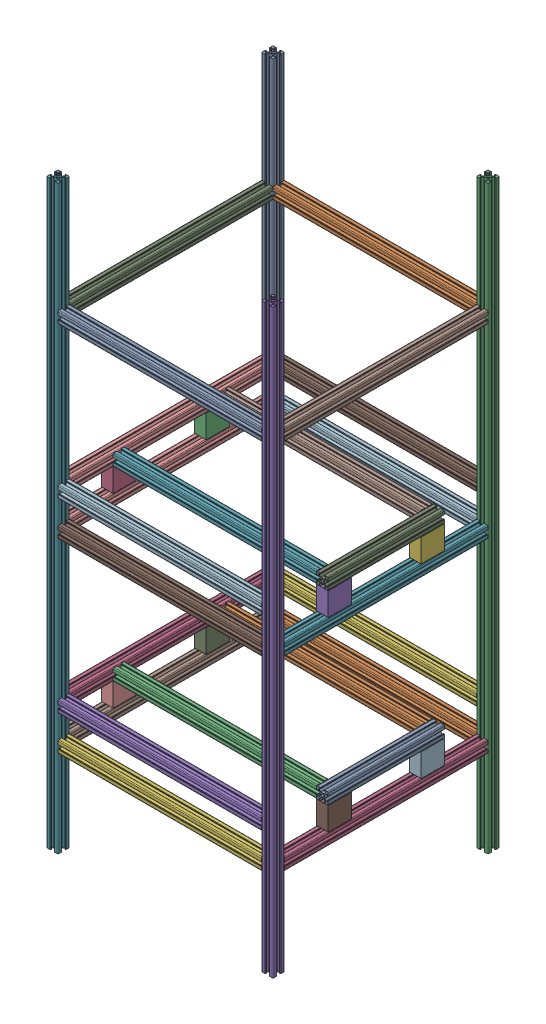
SolidWorks assembly 货架, configuration 默认. Lengths in mm.
Overall size (390 1000 390).
36 component instances, 4 part files, 105 mates.
Components (placement in the parent):
- 竖直1000型材1-1: 竖直1000型材1 [默认<按加工>] at (-170.1901 -508.4769 0) size (20 1000 20)
- 水平350型材1-1: 水平350型材1 [默认<按加工>] at (-160.1901 -348.4769 0) size (350 20 20)
- 竖直1000型材1-2: 竖直1000型材1 [默认<按加工>] at (199.8099 -508.4769 0) size (20 1000 20)
- 水平350型材1-2: 水平350型材1 [默认<按加工>] at (199.8099 -348.4769 10) x (0 0 1) z (-1 0 0) size (350 20 20)
- 竖直1000型材1-3: 竖直1000型材1 [默认<按加工>] at (199.8099 -508.4769 370) size (20 1000 20)
- 水平350型材1-3: 水平350型材1 [默认<按加工>] at (-160.1901 -348.4769 370) size (350 20 20)
- 竖直1000型材1-4: 竖直1000型材1 [默认<按加工>] at (-170.1901 -508.4769 370) size (20 1000 20)
- 水平350型材1-4: 水平350型材1 [默认<按加工>] at (-170.1901 -348.4769 10) x (0 0 1) z (-1 0 0) size (350 20 20)
- 垫高块40x40-1: 垫高块40x40 [默认] at (-180.1901 -338.4769 125) size (20 40 40)
- 垫高块40x40-2: 垫高块40x40 [默认] at (-180.1901 -338.4769 285) size (20 40 40)
- 垫高块40x40-3: 垫高块40x40 [默认] at (189.8099 -338.4769 285) size (20 40 40)
- 垫高块40x40-4: 垫高块40x40 [默认] at (189.8099 -338.4769 125) size (20 40 40)
- 水平200型材1-1: 水平200型材1 [默认<按加工>] at (199.8099 -288.4769 85) x (0 0 1) z (-1 0 0) size (200 20 20)
- 水平350型材1-5: 水平350型材1 [默认<按加工>] at (-160.1901 -288.4769 95) size (350 20 20)
- 水平350型材1-6: 水平350型材1 [默认<按加工>] at (-160.1901 -288.4769 275) size (350 20 20)
- 水平350型材1-7: 水平350型材1 [默认<按加工>] at (-170.1901 -288.4769 360) x (0 0 -1) z (1 0 0) size (350 20 20)
- 水平350型材1-8: 水平350型材1 [默认<按加工>] at (-160.1901 -288.4769 370) size (350 20 20)
- 水平350型材1-9: 水平350型材1 [默认<按加工>] at (-160.1901 -288.4769 0) size (350 20 20)
- 水平350型材1-10: 水平350型材1 [默认<按加工>] at (199.8099 -28.4769 10) x (0 0 1) z (-1 0 0) size (350 20 20)
- 水平350型材1-11: 水平350型材1 [默认<按加工>] at (199.8099 291.5231 10) x (0 0 1) z (-1 0 0) size (350 20 20)
- 水平350型材1-12: 水平350型材1 [默认<按加工>] at (-170.1901 291.5231 10) x (0 0 1) z (-1 0 0) size (350 20 20)
- 水平350型材1-13: 水平350型材1 [默认<按加工>] at (-170.1901 -28.4769 360) x (0 0 -1) z (1 0 0) size (350 20 20)
- 水平350型材1-14: 水平350型材1 [默认<按加工>] at (-160.1901 -28.4769 370) size (350 20 20)
- 水平350型材1-15: 水平350型材1 [默认<按加工>] at (-160.1901 -28.4769 0) size (350 20 20)
- 水平350型材1-16: 水平350型材1 [默认<按加工>] at (-160.1901 291.5231 370) size (350 20 20)
- 水平350型材1-17: 水平350型材1 [默认<按加工>] at (-160.1901 291.5231 0) size (350 20 20)
- 垫高块40x40-5: 垫高块40x40 [默认] at (-180.1901 -18.4769 125) size (20 40 40)
- 垫高块40x40-6: 垫高块40x40 [默认] at (-180.1901 -18.4769 285) size (20 40 40)
- 垫高块40x40-7: 垫高块40x40 [默认] at (189.8099 -18.4769 285) size (20 40 40)
- 垫高块40x40-8: 垫高块40x40 [默认] at (189.8099 -18.4769 125) size (20 40 40)
- 水平350型材1-18: 水平350型材1 [默认<按加工>] at (-160.1901 31.5231 275) size (350 20 20)
- 水平350型材1-19: 水平350型材1 [默认<按加工>] at (-160.1901 31.5231 95) size (350 20 20)
- 水平200型材1-3: 水平200型材1 [默认<按加工>] at (199.8099 31.5231 85) x (0 0 1) z (-1 0 0) size (200 20 20)
- 水平350型材1-20: 水平350型材1 [默认<按加工>] at (-170.1901 31.5231 10) x (0 0 1) z (-1 0 0) size (350 20 20)
- 水平350型材1-21: 水平350型材1 [默认<按加工>] at (-160.1901 31.5231 0) size (350 20 20)
- 水平350型材1-22: 水平350型材1 [默认<按加工>] at (-160.1901 31.5231 370) size (350 20 20)
Mates (geometry in assembly coordinates):
- 重合1: coincident anti-aligned: plane of 竖直1000型材1-1 through (-160.1901 491.5231 -8.5) normal (1 0 0); plane of 水平350型材1-1 through (-160.1901 -339.9769 8.5) normal (-1 0 0)
- 重合2: coincident aligned: plane of 竖直1000型材1-1 through (-166.5901 491.5231 10) normal (0 0 1); plane of 水平350型材1-1 through (189.8099 -344.8769 10) normal (0 0 1)
- 距离1: distance = 150 mm aligned: plane of 水平350型材1-1 through (189.8099 -358.4769 8.5) normal (0 -1 0); plane of 竖直1000型材1-1 through (-161.6901 -508.4769 8.5) normal (0 -1 0)
- 重合4: coincident anti-aligned: plane of 水平350型材1-1 through (189.8099 -339.9769 8.5) normal (1 0 0); plane of 竖直1000型材1-2 through (189.8099 491.5231 8.5) normal (-1 0 0)
- 重合5: coincident aligned: plane of 水平350型材1-1 through (189.8099 -344.8769 10) normal (0 0 1); plane of 竖直1000型材1-2 through (191.3099 491.5231 10) normal (0 0 1)
- 距离2: distance = 150 mm aligned: plane of 竖直1000型材1-2 through (208.3099 -508.4769 8.5) normal (0 -1 0); plane of 水平350型材1-1 through (189.8099 -358.4769 8.5) normal (0 -1 0)
- 重合7: coincident anti-aligned: plane of 竖直1000型材1-2 through (203.4099 491.5231 10) normal (0 0 1); plane of 水平350型材1-2 through (191.3099 -339.9769 10) normal (0 0 -1)
- 重合8: coincident aligned: plane of 竖直1000型材1-2 through (189.8099 491.5231 8.5) normal (-1 0 0); plane of 水平350型材1-2 through (189.8099 -344.8769 360) normal (-1 0 0)
- 重合9: coincident aligned: plane of 水平350型材1-1 through (189.8099 -338.4769 3.6) normal (0 1 0); plane of 水平350型材1-2 through (208.3099 -338.4769 360) normal (0 1 0)
- 重合10: coincident anti-aligned: plane of 水平350型材1-2 through (191.3099 -339.9769 360) normal (0 0 1); plane of 竖直1000型材1-3 through (208.3099 491.5231 360) normal (0 0 -1)
- 重合11: coincident aligned: plane of 水平350型材1-2 through (189.8099 -344.8769 360) normal (-1 0 0); plane of 竖直1000型材1-3 through (189.8099 491.5231 366.4) normal (-1 0 0)
- 距离3: distance = 150 mm aligned: plane of 竖直1000型材1-3 through (208.3099 -508.4769 378.5) normal (0 -1 0); plane of 水平350型材1-2 through (191.3099 -358.4769 360) normal (0 -1 0)
- 重合13: coincident anti-aligned: plane of 竖直1000型材1-3 through (189.8099 491.5231 378.5) normal (-1 0 0); plane of 水平350型材1-3 through (189.8099 -339.9769 378.5) normal (1 0 0)
- 重合14: coincident aligned: plane of 竖直1000型材1-3 through (191.3099 491.5231 380) normal (0 0 1); plane of 水平350型材1-3 through (189.8099 -344.8769 380) normal (0 0 1)
- 重合15: coincident aligned: plane of 水平350型材1-2 through (208.3099 -338.4769 360) normal (0 1 0); plane of 水平350型材1-3 through (189.8099 -338.4769 361.5) normal (0 1 0)
- 重合16: coincident anti-aligned: plane of 水平350型材1-3 through (-160.1901 -339.9769 378.5) normal (-1 0 0); plane of 竖直1000型材1-4 through (-160.1901 491.5231 361.5) normal (1 0 0)
- 重合17: coincident aligned: plane of 水平350型材1-3 through (189.8099 -344.8769 380) normal (0 0 1); plane of 竖直1000型材1-4 through (-166.5901 491.5231 380) normal (0 0 1)
- 距离4: distance = 150 mm aligned: plane of 竖直1000型材1-4 through (-161.6901 -508.4769 378.5) normal (0 -1 0); plane of 水平350型材1-3 through (189.8099 -358.4769 378.5) normal (0 -1 0)
- 重合19: coincident anti-aligned: plane of 竖直1000型材1-1 through (-166.5901 491.5231 10) normal (0 0 1); plane of 水平350型材1-4 through (-178.6901 -339.9769 10) normal (0 0 -1)
- 重合20: coincident aligned: plane of 竖直1000型材1-1 through (-180.1901 491.5231 8.5) normal (-1 0 0); plane of 水平350型材1-4 through (-180.1901 -344.8769 360) normal (-1 0 0)
- 重合21: coincident aligned: plane of 水平350型材1-3 through (189.8099 -338.4769 361.5) normal (0 1 0); plane of 水平350型材1-4 through (-161.6901 -338.4769 360) normal (0 1 0)
- 重合22: coincident anti-aligned: plane of 水平350型材1-4 through (-161.6901 -338.4769 360) normal (0 1 0); plane of 垫高块40x40-1 through (-160.1901 -338.4769 125) normal (0 -1 0)
- 重合23: coincident aligned: plane of 水平350型材1-4 through (-180.1901 -344.8769 360) normal (-1 0 0); plane of 垫高块40x40-1 through (-180.1901 -338.4769 125) normal (-1 0 0)
- 距离5: distance = 75 mm anti-aligned: plane of 垫高块40x40-1 through (-160.1901 -338.4769 85) normal (0 0 -1); plane of 竖直1000型材1-1 through (-166.5901 491.5231 10) normal (0 0 1)
- 重合25: coincident anti-aligned: plane of 水平350型材1-4 through (-161.6901 -338.4769 360) normal (0 1 0); plane of 垫高块40x40-2 through (-160.1901 -338.4769 285) normal (0 -1 0)
- 重合26: coincident aligned: plane of 水平350型材1-4 through (-180.1901 -344.8769 360) normal (-1 0 0); plane of 垫高块40x40-2 through (-180.1901 -338.4769 285) normal (-1 0 0)
- 距离6: distance = 75 mm anti-aligned: plane of 垫高块40x40-2 through (-160.1901 -338.4769 285) normal (0 0 1); plane of 竖直1000型材1-4 through (-161.6901 491.5231 360) normal (0 0 -1)
- 重合28: coincident anti-aligned: plane of 水平350型材1-2 through (196.2099 -338.4769 360) normal (0 1 0); plane of 垫高块40x40-3 through (209.8099 -338.4769 285) normal (0 -1 0)
- 重合29: coincident aligned: plane of 水平350型材1-2 through (209.8099 -352.0769 360) normal (1 0 0); plane of 垫高块40x40-3 through (209.8099 -338.4769 285) normal (1 0 0)
- 距离7: distance = 75 mm anti-aligned: plane of 竖直1000型材1-3 through (196.2099 491.5231 360) normal (0 0 -1); plane of 垫高块40x40-3 through (209.8099 -338.4769 285) normal (0 0 1)
- 重合30: coincident aligned: plane of 水平350型材1-2 through (209.8099 -339.9769 360) normal (1 0 0); plane of 垫高块40x40-4 through (209.8099 -338.4769 125) normal (1 0 0)
- 重合32: coincident anti-aligned: plane of 水平350型材1-2 through (196.2099 -338.4769 360) normal (0 1 0); plane of 垫高块40x40-4 through (209.8099 -338.4769 125) normal (0 -1 0)
- 距离8: distance = 75 mm anti-aligned: plane of 垫高块40x40-4 through (209.8099 -338.4769 85) normal (0 0 -1); plane of 竖直1000型材1-2 through (191.3099 491.5231 10) normal (0 0 1)
- 重合34: coincident aligned: plane of 垫高块40x40-3 through (209.8099 -338.4769 285) normal (0 0 1); plane of 水平200型材1-1 through (191.3099 -279.9769 285) normal (0 0 1)
- 重合35: coincident anti-aligned: plane of 垫高块40x40-3 through (209.8099 -298.4769 285) normal (0 1 0); plane of 水平200型材1-1 through (203.4099 -298.4769 285) normal (0 -1 0)
- 重合36: coincident aligned: plane of 垫高块40x40-3 through (209.8099 -338.4769 285) normal (1 0 0); plane of 水平200型材1-1 through (209.8099 -279.9769 285) normal (1 0 0)
- 重合40: coincident anti-aligned: plane of 水平200型材1-1 through (189.8099 -284.8769 285) normal (-1 0 0); plane of 水平350型材1-5 through (189.8099 -279.9769 103.5) normal (1 0 0)
- 重合41: coincident aligned: plane of 水平200型材1-1 through (208.3099 -278.4769 285) normal (0 1 0); plane of 水平350型材1-5 through (189.8099 -278.4769 98.6) normal (0 1 0)
- 重合42: coincident aligned: plane of 水平200型材1-1 through (191.3099 -279.9769 85) normal (0 0 -1); plane of 水平350型材1-5 through (189.8099 -279.9769 85) normal (0 0 -1)
- 重合46: coincident anti-aligned: plane of 竖直1000型材1-4 through (-161.6901 491.5231 360) normal (0 0 -1); plane of 水平350型材1-7 through (-161.6901 -279.9769 360) normal (0 0 1)
- 重合47: coincident anti-aligned: plane of 水平350型材1-5 through (-160.1901 -279.9769 103.5) normal (-1 0 0); plane of 水平350型材1-7 through (-160.1901 -284.8769 10) normal (1 0 0)
- 重合48: coincident anti-aligned: plane of 垫高块40x40-1 through (-160.1901 -298.4769 125) normal (0 1 0); plane of 水平350型材1-7 through (-173.7901 -298.4769 10) normal (0 -1 0)
- 重合49: coincident aligned: plane of 水平200型材1-1 through (191.3099 -279.9769 285) normal (0 0 1); plane of 水平350型材1-6 through (189.8099 -284.8769 285) normal (0 0 1)
- 重合50: coincident aligned: plane of 水平200型材1-1 through (196.2099 -278.4769 285) normal (0 1 0); plane of 水平350型材1-6 through (189.8099 -278.4769 278.6) normal (0 1 0)
- 重合51: coincident anti-aligned: plane of 水平200型材1-1 through (189.8099 -284.8769 285) normal (-1 0 0); plane of 水平350型材1-6 through (189.8099 -279.9769 283.5) normal (1 0 0)
- 重合55: coincident aligned: plane of 竖直1000型材1-3 through (191.3099 491.5231 380) normal (0 0 1); plane of 水平350型材1-8 through (189.8099 -284.8769 380) normal (0 0 1)
- 重合57: coincident anti-aligned: plane of 竖直1000型材1-4 through (-160.1901 491.5231 361.5) normal (1 0 0); plane of 水平350型材1-8 through (-160.1901 -279.9769 378.5) normal (-1 0 0)
- 重合58: coincident aligned: plane of 水平350型材1-6 through (189.8099 -278.4769 266.5) normal (0 1 0); plane of 水平350型材1-8 through (189.8099 -278.4769 361.5) normal (0 1 0)
- 重合59: coincident anti-aligned: plane of 竖直1000型材1-2 through (189.8099 491.5231 8.5) normal (-1 0 0); plane of 水平350型材1-9 through (189.8099 -279.9769 8.5) normal (1 0 0)
- 重合60: coincident aligned: plane of 竖直1000型材1-2 through (191.3099 491.5231 10) normal (0 0 1); plane of 水平350型材1-9 through (189.8099 -296.9769 10) normal (0 0 1)
- 重合61: coincident aligned: plane of 水平350型材1-5 through (189.8099 -278.4769 86.5) normal (0 1 0); plane of 水平350型材1-9 through (189.8099 -278.4769 3.6) normal (0 1 0)
- 重合62: coincident anti-aligned: plane of 竖直1000型材1-3 through (196.2099 491.5231 360) normal (0 0 -1); plane of 水平350型材1-10 through (191.3099 -19.9769 360) normal (0 0 1)
- 重合63: coincident aligned: plane of 竖直1000型材1-3 through (209.8099 491.5231 361.5) normal (1 0 0); plane of 水平350型材1-10 through (209.8099 -19.9769 360) normal (1 0 0)
- 距离9: distance = 300 mm anti-aligned: plane of 水平350型材1-10 through (203.4099 -38.4769 360) normal (0 -1 0); plane of 水平350型材1-2 through (196.2099 -338.4769 360) normal (0 1 0)
- 重合65: coincident anti-aligned: plane of 竖直1000型材1-3 through (196.2099 491.5231 360) normal (0 0 -1); plane of 水平350型材1-11 through (191.3099 300.0231 360) normal (0 0 1)
- 重合66: coincident aligned: plane of 竖直1000型材1-3 through (209.8099 491.5231 361.5) normal (1 0 0); plane of 水平350型材1-11 through (209.8099 300.0231 360) normal (1 0 0)
- 距离10: distance = 300 mm anti-aligned: plane of 水平350型材1-11 through (203.4099 281.5231 360) normal (0 -1 0); plane of 水平350型材1-10 through (208.3099 -18.4769 360) normal (0 1 0)
- 重合68: coincident anti-aligned: plane of 竖直1000型材1-1 through (-166.5901 491.5231 10) normal (0 0 1); plane of 水平350型材1-12 through (-178.6901 300.0231 10) normal (0 0 -1)
- 重合69: coincident aligned: plane of 竖直1000型材1-1 through (-180.1901 491.5231 8.5) normal (-1 0 0); plane of 水平350型材1-12 through (-180.1901 295.1231 360) normal (-1 0 0)
- 重合70: coincident aligned: plane of 水平350型材1-11 through (208.3099 301.5231 360) normal (0 1 0); plane of 水平350型材1-12 through (-161.6901 301.5231 360) normal (0 1 0)
- 重合71: coincident anti-aligned: plane of 竖直1000型材1-4 through (-173.7901 491.5231 360) normal (0 0 -1); plane of 水平350型材1-13 through (-161.6901 -19.9769 360) normal (0 0 1)
- 重合72: coincident aligned: plane of 竖直1000型材1-4 through (-180.1901 491.5231 378.5) normal (-1 0 0); plane of 水平350型材1-13 through (-180.1901 -19.9769 10) normal (-1 0 0)
- 重合73: coincident aligned: plane of 水平350型材1-10 through (208.3099 -18.4769 360) normal (0 1 0); plane of 水平350型材1-13 through (-166.5901 -18.4769 10) normal (0 1 0)
- 重合74: coincident anti-aligned: plane of 竖直1000型材1-3 through (189.8099 491.5231 378.5) normal (-1 0 0); plane of 水平350型材1-14 through (189.8099 -19.9769 378.5) normal (1 0 0)
- 重合75: coincident aligned: plane of 水平350型材1-10 through (208.3099 -18.4769 360) normal (0 1 0); plane of 水平350型材1-14 through (189.8099 -18.4769 361.5) normal (0 1 0)
- 重合76: coincident aligned: plane of 竖直1000型材1-3 through (191.3099 491.5231 380) normal (0 0 1); plane of 水平350型材1-14 through (189.8099 -24.8769 380) normal (0 0 1)
- 重合77: coincident aligned: plane of 竖直1000型材1-2 through (196.2099 491.5231 -10) normal (0 0 -1); plane of 水平350型材1-15 through (189.8099 -19.9769 -10) normal (0 0 -1)
- 重合78: coincident anti-aligned: plane of 竖直1000型材1-2 through (189.8099 491.5231 -3.6) normal (-1 0 0); plane of 水平350型材1-15 through (189.8099 -19.9769 8.5) normal (1 0 0)
- 重合79: coincident aligned: plane of 水平350型材1-13 through (-166.5901 -18.4769 10) normal (0 1 0); plane of 水平350型材1-15 through (189.8099 -18.4769 3.6) normal (0 1 0)
- 重合80: coincident anti-aligned: plane of 竖直1000型材1-4 through (-160.1901 491.5231 361.5) normal (1 0 0); plane of 水平350型材1-16 through (-160.1901 300.0231 378.5) normal (-1 0 0)
- 重合81: coincident aligned: plane of 竖直1000型材1-4 through (-166.5901 491.5231 380) normal (0 0 1); plane of 水平350型材1-16 through (189.8099 295.1231 380) normal (0 0 1)
- 重合82: coincident aligned: plane of 水平350型材1-12 through (-161.6901 301.5231 360) normal (0 1 0); plane of 水平350型材1-16 through (189.8099 301.5231 361.5) normal (0 1 0)
- 重合83: coincident aligned: plane of 竖直1000型材1-2 through (208.3099 491.5231 -10) normal (0 0 -1); plane of 水平350型材1-17 through (189.8099 300.0231 -10) normal (0 0 -1)
- 重合84: coincident anti-aligned: plane of 竖直1000型材1-1 through (-160.1901 491.5231 -8.5) normal (1 0 0); plane of 水平350型材1-17 through (-160.1901 300.0231 8.5) normal (-1 0 0)
- 重合85: coincident aligned: plane of 水平350型材1-12 through (-161.6901 301.5231 360) normal (0 1 0); plane of 水平350型材1-17 through (189.8099 301.5231 3.6) normal (0 1 0)
- 重合86: coincident aligned: plane of 水平350型材1-13 through (-180.1901 -19.9769 10) normal (-1 0 0); plane of 垫高块40x40-5 through (-180.1901 -18.4769 125) normal (-1 0 0)
- 重合87: coincident anti-aligned: plane of 水平350型材1-13 through (-178.6901 -18.4769 10) normal (0 1 0); plane of 垫高块40x40-5 through (-160.1901 -18.4769 125) normal (0 -1 0)
- 距离11: distance = 75 mm anti-aligned: plane of 垫高块40x40-5 through (-160.1901 -18.4769 85) normal (0 0 -1); plane of 竖直1000型材1-1 through (-166.5901 491.5231 10) normal (0 0 1)
- 重合89: coincident aligned: plane of 水平350型材1-13 through (-180.1901 -19.9769 10) normal (-1 0 0); plane of 垫高块40x40-6 through (-180.1901 -18.4769 285) normal (-1 0 0)
- 重合90: coincident anti-aligned: plane of 水平350型材1-13 through (-166.5901 -18.4769 10) normal (0 1 0); plane of 垫高块40x40-6 through (-160.1901 -18.4769 285) normal (0 -1 0)
- 距离12: distance = 75 mm anti-aligned: plane of 垫高块40x40-6 through (-160.1901 -18.4769 285) normal (0 0 1); plane of 竖直1000型材1-4 through (-161.6901 491.5231 360) normal (0 0 -1)
- 重合92: coincident aligned: plane of 水平350型材1-10 through (209.8099 -19.9769 360) normal (1 0 0); plane of 垫高块40x40-7 through (209.8099 -18.4769 285) normal (1 0 0)
- 重合93: coincident anti-aligned: plane of 水平350型材1-10 through (196.2099 -18.4769 360) normal (0 1 0); plane of 垫高块40x40-7 through (209.8099 -18.4769 285) normal (0 -1 0)
- 距离13: distance = 75 mm anti-aligned: plane of 垫高块40x40-7 through (209.8099 -18.4769 285) normal (0 0 1); plane of 竖直1000型材1-3 through (196.2099 491.5231 360) normal (0 0 -1)
- 重合95: coincident aligned: plane of 水平350型材1-10 through (209.8099 -19.9769 360) normal (1 0 0); plane of 垫高块40x40-8 through (209.8099 -18.4769 125) normal (1 0 0)
- 重合96: coincident anti-aligned: plane of 水平350型材1-10 through (196.2099 -18.4769 360) normal (0 1 0); plane of 垫高块40x40-8 through (209.8099 -18.4769 125) normal (0 -1 0)
- 距离14: distance = 75 mm anti-aligned: plane of 垫高块40x40-8 through (209.8099 -18.4769 85) normal (0 0 -1); plane of 竖直1000型材1-2 through (191.3099 491.5231 10) normal (0 0 1)
- 重合98: coincident anti-aligned: plane of 垫高块40x40-7 through (189.8099 -18.4769 285) normal (-1 0 0); plane of 水平350型材1-18 through (189.8099 40.0231 283.5) normal (1 0 0)
- 重合99: coincident anti-aligned: plane of 垫高块40x40-7 through (209.8099 21.5231 285) normal (0 1 0); plane of 水平350型材1-18 through (189.8099 21.5231 283.5) normal (0 -1 0)
- 重合100: coincident aligned: plane of 垫高块40x40-7 through (209.8099 -18.4769 285) normal (0 0 1); plane of 水平350型材1-18 through (189.8099 35.1231 285) normal (0 0 1)
- 重合101: coincident anti-aligned: plane of 垫高块40x40-8 through (189.8099 -18.4769 125) normal (-1 0 0); plane of 水平350型材1-19 through (189.8099 40.0231 103.5) normal (1 0 0)
- 重合102: coincident anti-aligned: plane of 垫高块40x40-8 through (209.8099 21.5231 125) normal (0 1 0); plane of 水平350型材1-19 through (189.8099 21.5231 91.4) normal (0 -1 0)
- 重合103: coincident aligned: plane of 垫高块40x40-8 through (209.8099 -18.4769 85) normal (0 0 -1); plane of 水平350型材1-19 through (189.8099 40.0231 85) normal (0 0 -1)
- 重合104: coincident aligned: plane of 垫高块40x40-7 through (209.8099 -18.4769 285) normal (0 0 1); plane of 水平200型材1-3 through (191.3099 40.0231 285) normal (0 0 1)
- 重合105: coincident anti-aligned: plane of 垫高块40x40-7 through (209.8099 21.5231 285) normal (0 1 0); plane of 水平200型材1-3 through (203.4099 21.5231 285) normal (0 -1 0)
- 重合106: coincident anti-aligned: plane of 水平350型材1-18 through (189.8099 40.0231 283.5) normal (1 0 0); plane of 水平200型材1-3 through (189.8099 35.1231 285) normal (-1 0 0)
- 重合110: coincident anti-aligned: plane of 竖直1000型材1-1 through (-166.5901 491.5231 10) normal (0 0 1); plane of 水平350型材1-20 through (-178.6901 40.0231 10) normal (0 0 -1)
- 重合111: coincident aligned: plane of 竖直1000型材1-1 through (-180.1901 491.5231 8.5) normal (-1 0 0); plane of 水平350型材1-20 through (-180.1901 35.1231 360) normal (-1 0 0)
- 重合112: coincident anti-aligned: plane of 垫高块40x40-5 through (-160.1901 21.5231 125) normal (0 1 0); plane of 水平350型材1-20 through (-178.6901 21.5231 360) normal (0 -1 0)
- 重合113: coincident anti-aligned: plane of 竖直1000型材1-2 through (189.8099 491.5231 8.5) normal (-1 0 0); plane of 水平350型材1-21 through (189.8099 40.0231 8.5) normal (1 0 0)
- 重合114: coincident aligned: plane of 水平350型材1-19 through (189.8099 41.5231 98.6) normal (0 1 0); plane of 水平350型材1-21 through (189.8099 41.5231 3.6) normal (0 1 0)
- 重合116: coincident aligned: plane of 竖直1000型材1-2 through (196.2099 491.5231 -10) normal (0 0 -1); plane of 水平350型材1-21 through (189.8099 40.0231 -10) normal (0 0 -1)
- 重合117: coincident: plane of 竖直1000型材1-4 through (-166.5901 491.5231 380) normal (0 0 1); plane of 水平350型材1-22 through (223.0043 36.8159 300.973) normal (0 0 1)
- 重合118: coincident: plane of 竖直1000型材1-3 through (189.8099 491.5231 366.4) normal (-1 0 0); plane of 水平350型材1-22 through (223.0043 41.7159 299.473) normal (1 0 0)
- 重合120: coincident aligned: plane of 水平350型材1-18 through (189.8099 41.5231 278.6) normal (0 1 0); plane of 水平350型材1-22 through (189.8099 41.5231 361.5) normal (0 1 0)
